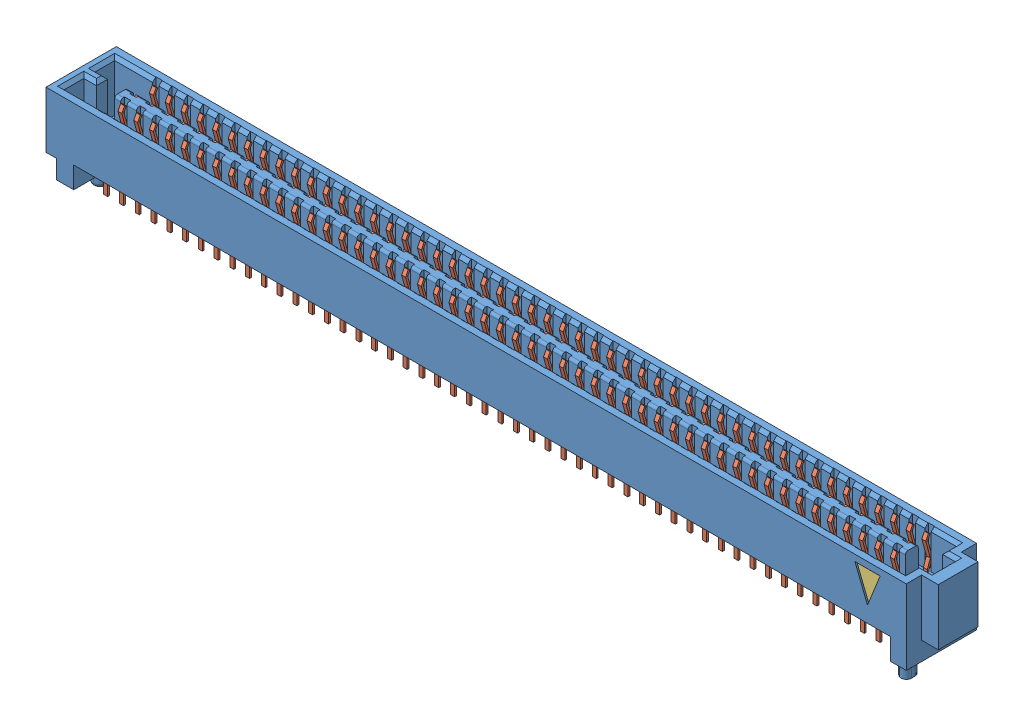
SolidWorks assembly SEAF-50-06.0-L-04-2-A-K-TR, configuration Default. Lengths in mm.
Overall size (70.66 7.32 5.66).
5 component instances, 4 part files, 3 mates.
Components (placement in the parent):
- SEAF_50_06_0_L_04_2_A_K_TR-1: SEAF_50_06_0_L_04_2_A_K_TR [Default] at (0.254 1.7272 0) size (70.66 7.32 5.66)
  - _SEAF_50_06_0_L_04_1_A_0_K_TR_BODY_2_2-1: _SEAF_50_06_0_L_04_1_A_0_K_TR_BODY_2_2 [Default] at origin size (70.66 7.32 5.66)
  - _SEAF_50_06_0_L_04_1_A_0_K_TR_cCON2_4-1: _SEAF_50_06_0_L_04_1_A_0_K_TR_cCON2_4 [Default] at origin size (62.55 5.65 5.41)
  - _SEAF_04_K_PAD_6-1: _SEAF_04_K_PAD_6 [Default] at (-0.2286 4.318 0) size (6.5 0.13 6.5) (hidden)
  - _SEAF_TRIANGLE_FIRST_PIN_8-1: _SEAF_TRIANGLE_FIRST_PIN_8 [Default] at (30.861 0.762 2.5781) size (2.03 2.54 0.13)
Mates (geometry in assembly coordinates):
- Coincident1: coincident: plane of ? through (0.254 0 0) normal (0 -1 0)
- Coincident2: coincident: line of ? through (-4.9332 0 1.7272) axis (0 1 0)
- Coincident3: coincident: plane of ? through (0.254 1.7272 0) normal (0 0 -1)
